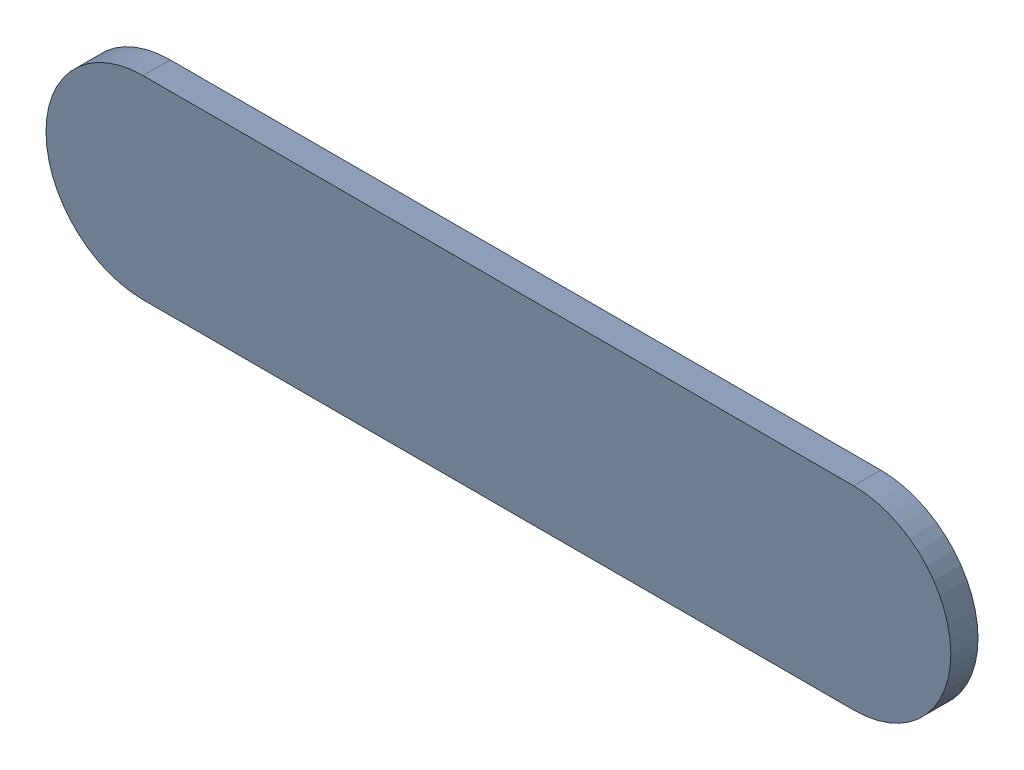
SolidWorks assembly Track (20.109mm,47.265mm)(21.039mm,47.265mm) on Bottom Layer, configuration Predeterminado. Lengths in mm.
Overall size (1.18 0.25 0.04).
2 component instances, 1 part files, 0 mates.
Components (placement in the parent):
- Track (20.109mm,47.265mm)(21.039mm,47.265mm) on Bottom Layer-1-1: Track (20.109mm,47.265mm)(21.039mm,47.265mm) on Bottom Layer-1 [Predeterminado] at (-68.317 -44.187 -0.4013) size (1.18 0.25 0.04)
  - Track (20.109mm,47.265mm)(21.039mm,47.265mm) on Bottom Layer-Part-1-1: Track (20.109mm,47.265mm)(21.039mm,47.265mm) on Bottom Layer-Part-1 [Predeterminado] at origin size (1.18 0.25 0.04)
